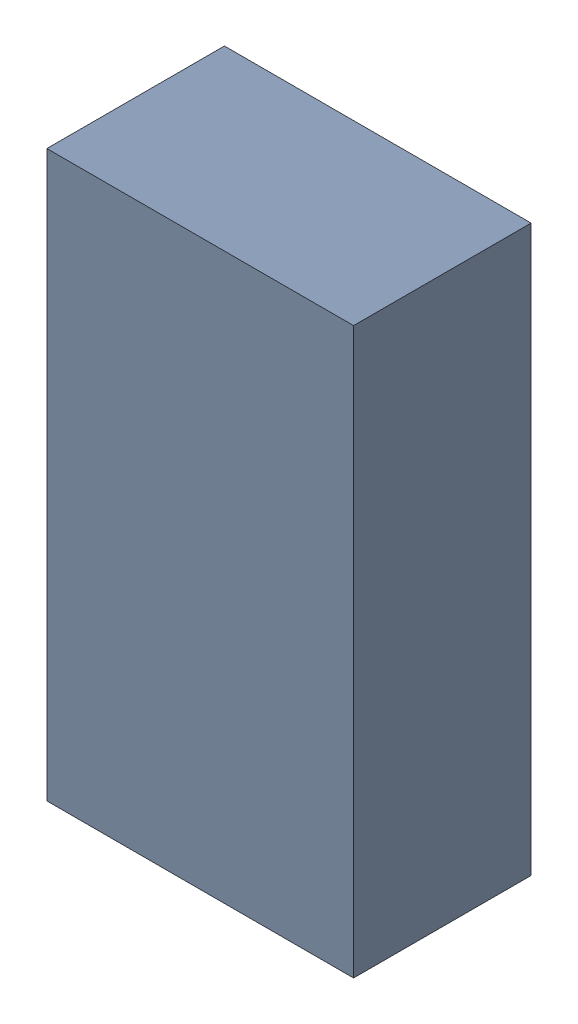
SolidWorks assembly L3_TDA4, configuration Standard. Lengths in mm.
Overall size (0.95 1.75 0.55).
2 component instances, 1 part files, 0 mates.
Components (placement in the parent):
- 885542784-1: 885542784 [Standard] at (-3.19 -58.48 0) size (0.95 1.75 0.55)
  - Extruded_22-1: Extruded_22 [Standard] at origin size (0.95 1.75 0.55)
